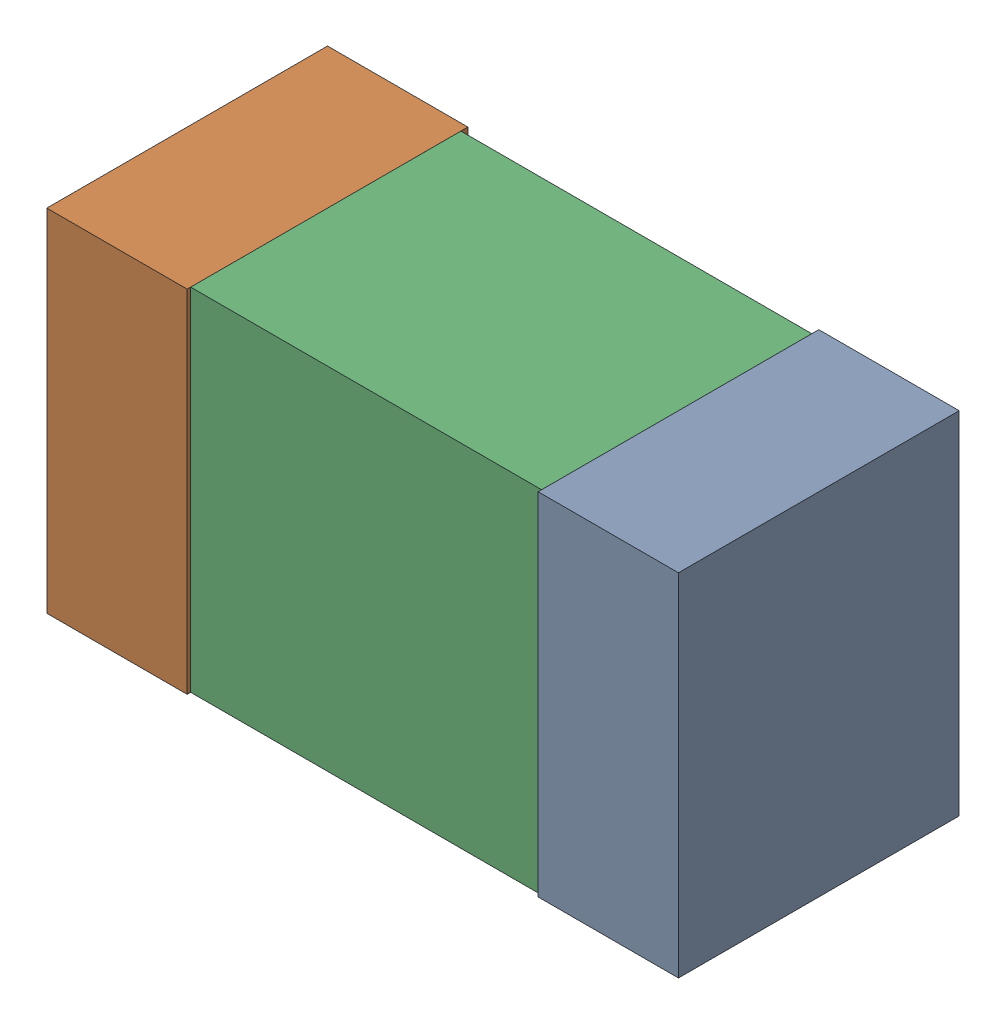
SolidWorks assembly L405PCB, configuration Default. Lengths in mm.
Overall size (1.8 1 0.8).
6 component instances, 2 part files, 0 mates.
Components (placement in the parent):
- 854785840-1: 854785840 [Default] at (117.7001 98.7999 -2.4638) size (0.4 1 0.8)
  - Extruded_4-1: Extruded_4 [Default] at origin size (0.4 1 0.8)
- 854785840-2: 854785840 [Default] at (116.3001 98.7999 -2.4638) size (0.4 1 0.8)
  - Extruded_4-1: Extruded_4 [Default] at origin size (0.4 1 0.8)
- 846483152-1: 846483152 [Default] at (117.0001 98.7999 -2.4438) size (1 1 0.77)
  - Extruded_3-1: Extruded_3 [Default] at origin size (1 1 0.77)
